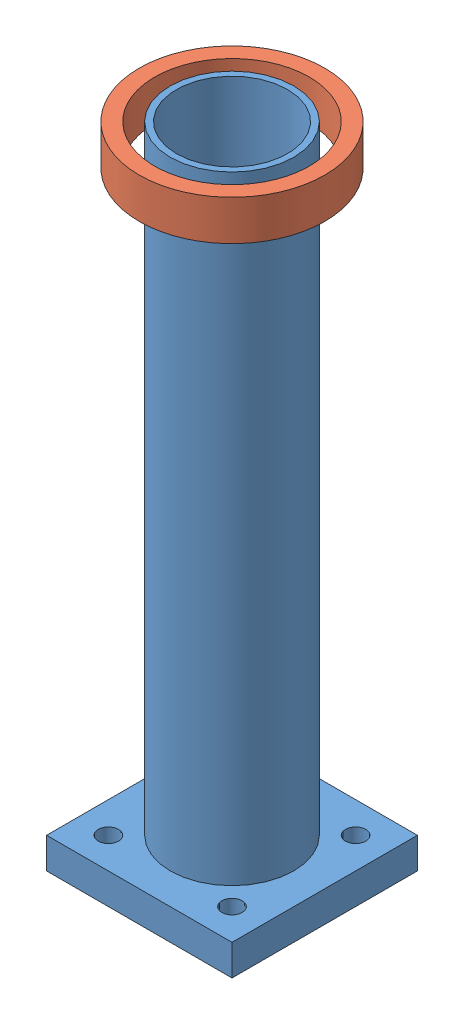
SolidWorks assembly BE101-01Z-04Z 烟囱与圈, configuration 默认. Lengths in mm.
Overall size (60 210 60).
2 component instances, 2 part files, 5 mates.
Components (placement in the parent):
- BE101-01Z-004 中空立柱-1: BE101-01Z-004 中空立柱 [默认] at origin size (60 210 60)
- BE101-01Z-006 轴承外圈-1: BE101-01Z-006 轴承外圈 [默认] at (0 193.5 0) size (60 13 60)
Mates (geometry in assembly coordinates):
- Concentric1: concentric aligned: cylinder of BE101-01Z-004 中空立柱-1 through (0 200 0) axis (0 -1 0) radius 20; cylinder of BE101-01Z-006 轴承外圈-1 through (0 200 0) axis (0 -1 0) radius 25
- 重合1: coincident aligned: plane of BE101-01Z-004 中空立柱-1 through (0 200 0) normal (0 1 0); plane of BE101-01Z-006 轴承外圈-1 through (0 200 0) normal (0 1 0)
- 重合2: coincident aligned: plane of BE101-01Z-004 中空立柱-1 through (0 0 0) normal (0 0 1)
- 重合3: coincident aligned: plane of BE101-01Z-004 中空立柱-1 through (0 0 0) normal (0 1 0)
- 重合4: coincident aligned: plane of BE101-01Z-004 中空立柱-1 through (0 0 0) normal (1 0 0)
